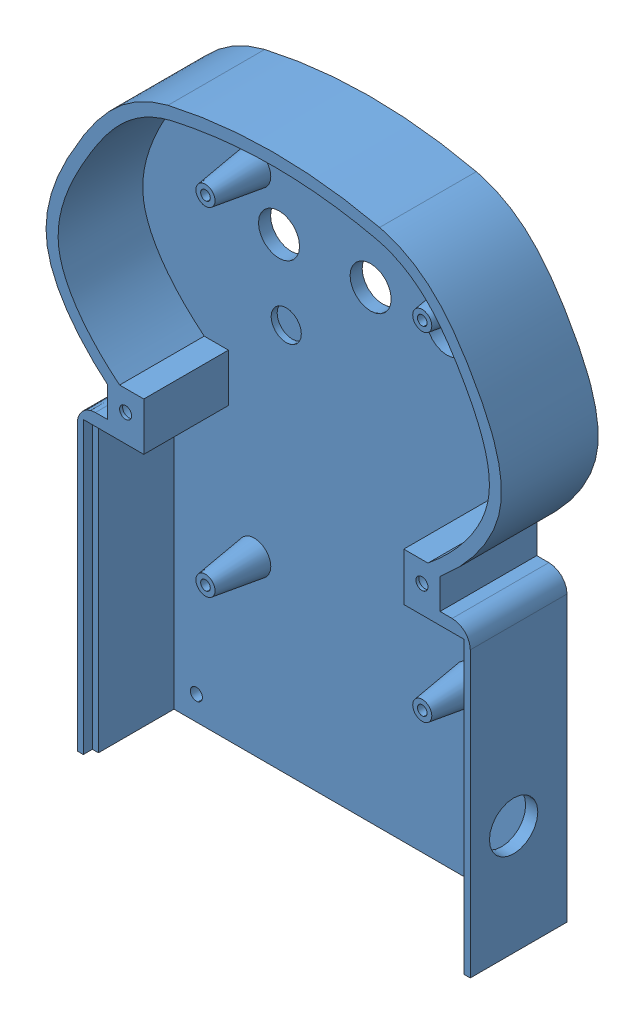
SolidWorks assembly assemblage buste avant arrière, configuration Défaut. Lengths in mm.
Overall size (82.39 102 16).
2 component instances, 2 part files, 3 mates.
Components (placement in the parent):
- buste avant-1: buste avant [Défaut] at (-80.3384 -59.7932 -32.25) size (82.39 102 35.5) (hidden)
- Buste arrière-1: Buste arrière [Défaut] at (-80.3384 -59.7932 -32.25) size (82.39 102 16)
Mates (geometry in assembly coordinates):
- Coïncidente1: coincident anti-aligned: plane of buste avant-1 through (-17.3384 -59.7932 -16.25) normal (0 0 -1); plane of Buste arrière-1 through (-17.3384 -59.7932 -16.25) normal (0 0 1)
- Coïncidente3: coincident aligned: plane of buste avant-1 through (-15.3384 -59.7932 17.75) normal (1 0 0); plane of Buste arrière-1 through (-15.3384 -59.7932 17.75) normal (1 0 0)
- Coïncidente4: coincident aligned: plane of buste avant-1 through (-80.3384 -59.7932 17.75) normal (0 -1 0); plane of Buste arrière-1 through (-80.3384 -59.7932 17.75) normal (0 -1 0)
